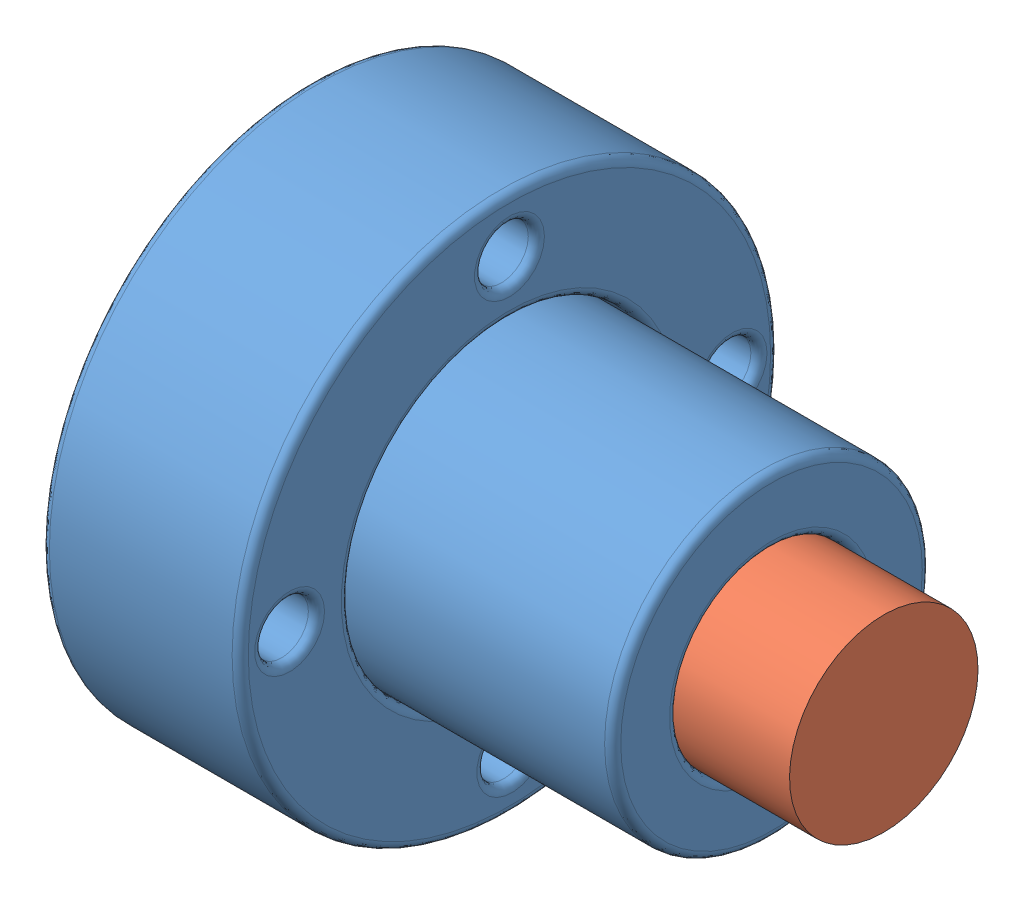
SolidWorks assembly Assem1, configuration Default. Lengths in mm.
Overall size (212.47 200 200).
2 component instances, 2 part files, 2 mates.
Components (placement in the parent):
- Part2-1: Part2 [Default] at (25.8691 124.723 165.4337) size (170.91 200 200)
- part assem-1: part assem [Default] at (229.4522 123.3694 164.9909) x (0 -0.112893 0.993607) z (1 0 0) size (70 70 209)
Mates (geometry in assembly coordinates):
- Concentric1: concentric anti-aligned: cylinder of Part2-1 through (21.9842 123.3694 164.9909) axis (1 0 0) radius 35; cylinder of part assem-1 through (117.4522 123.3694 164.9909) axis (1 0 0) radius 35
- Coincident2: coincident anti-aligned: plane of Part2-1 through (25.4522 124.723 165.4337) normal (1 0 0); plane of part assem-1
